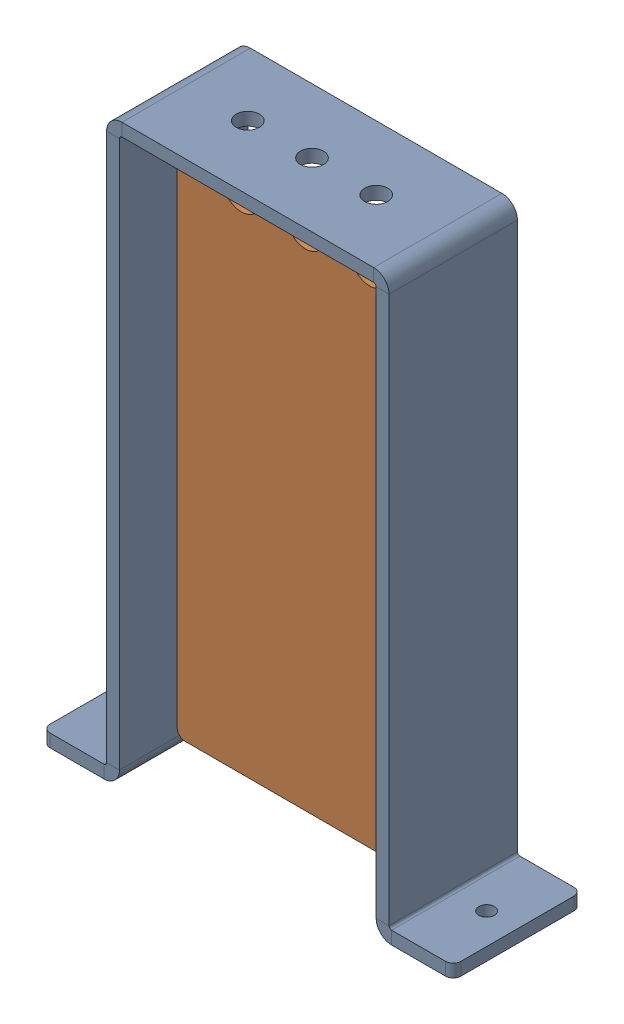
SolidWorks assembly Ground-Cover Base Assembly, configuration Default. Lengths in mm.
Overall size (160 225 50).
2 component instances, 2 part files, 4 mates.
Components (placement in the parent):
- ground-cover base bracket-1: ground-cover base bracket [Default] at origin size (160 225 50)
- reinforced ground-cover base bracket-1: reinforced ground-cover base bracket [Default] at (0 6 0) size (100 213 5)
Mates (geometry in assembly coordinates):
- Coincident1: coordinate: point of chan de nap che mat dat-1
- Coincident2: coincident anti-aligned: plane of chan de nap che mat dat - gia cuong-1 through (-50 6 2.5) normal (0 -1 0); line of chan de nap che mat dat-1 through (-50 6 25) axis (0 0 -1)
- Coincident3: coincident anti-aligned: plane of chan de nap che mat dat-1 through (50 220 25) normal (-1 0 0); plane of chan de nap che mat dat - gia cuong-1 through (50 6 2.5) normal (1 0 0)
- Coincident4: coincident aligned: plane of chan de nap che mat dat-1 through (0 0 0) normal (0 0 1); plane of chan de nap che mat dat - gia cuong-1 through (0 6 0) normal (0 0 1)
